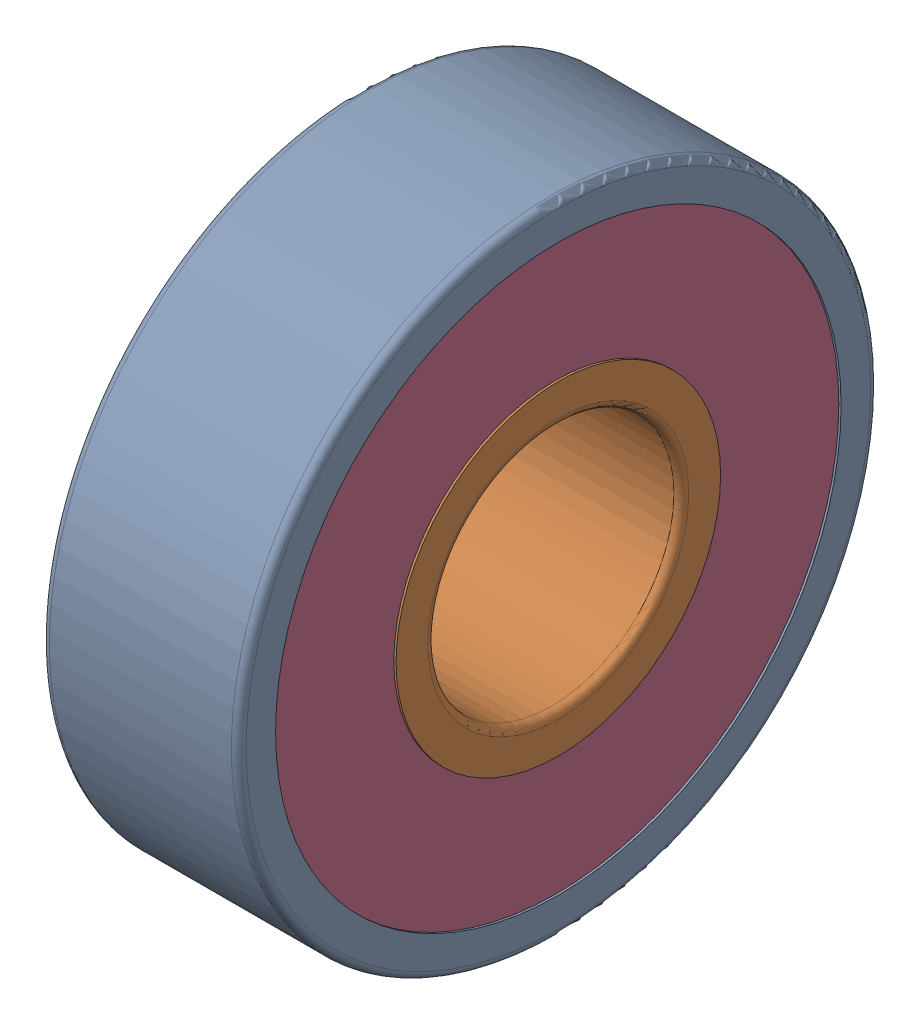
SolidWorks assembly 6000DDU, configuration Default. Lengths in mm.
Overall size (8 26 26).
17 component instances, 5 part files, 0 mates.
Components (placement in the parent):
- 6000DDU Outer ring-1: 6000DDU Outer ring [Default] at origin size (8 26 26)
- 6000DDU Inner ring-1: 6000DDU Inner ring [Default] x (1 0 0) z (0 1 0) size (8 14.57 14.57)
- 6000DDU Ball-1: 6000DDU Ball [Default] at (4 0 -9) x (1 0 0) z (0 1 0) size (4 4 4)
- 6000DDU Ball-2: 6000DDU Ball [Default] at (4 4.1825 -7.9691) x (1 0 0) z (0 1 0) size (4 4 4)
- 6000DDU Ball-3: 6000DDU Ball [Default] at (4 7.4069 -5.1126) x (1 0 0) z (0 1 0) size (4 4 4)
- 6000DDU Ball-4: 6000DDU Ball [Default] at (4 8.9344 -1.0848) x (1 0 0) z (0 1 0) size (4 4 4)
- 6000DDU Ball-5: 6000DDU Ball [Default] at (4 8.4151 3.1914) x (1 0 0) z (0 1 0) size (4 4 4)
- 6000DDU Ball-6: 6000DDU Ball [Default] at (4 5.9681 6.7366) x (1 0 0) z (0 1 0) size (4 4 4)
- 6000DDU Ball-7: 6000DDU Ball [Default] at (4 2.1538 8.7385) x (1 0 0) z (0 1 0) size (4 4 4)
- 6000DDU Ball-8: 6000DDU Ball [Default] at (4 -2.1538 8.7385) x (1 0 0) z (0 1 0) size (4 4 4)
- 6000DDU Ball-9: 6000DDU Ball [Default] at (4 -5.9681 6.7366) x (1 0 0) z (0 1 0) size (4 4 4)
- 6000DDU Ball-10: 6000DDU Ball [Default] at (4 -8.4151 3.1914) x (1 0 0) z (0 1 0) size (4 4 4)
- 6000DDU Ball-11: 6000DDU Ball [Default] at (4 -8.9344 -1.0848) x (1 0 0) z (0 1 0) size (4 4 4)
- 6000DDU Ball-12: 6000DDU Ball [Default] at (4 -7.4069 -5.1126) x (1 0 0) z (0 1 0) size (4 4 4)
- 6000DDU Ball-13: 6000DDU Ball [Default] at (4 -4.1825 -7.9691) x (1 0 0) z (0 1 0) size (4 4 4)
- 6000DDU Shield1-1: 6000DDU Shield1 [Default] at (7.632 0 0) size (0.28 23 23)
- 6000DDU Shield2-1: 6000DDU Shield2 [Default] at (0.368 0 0) x (-1 0 0) z (0 0 1) size (0.28 23 23)
